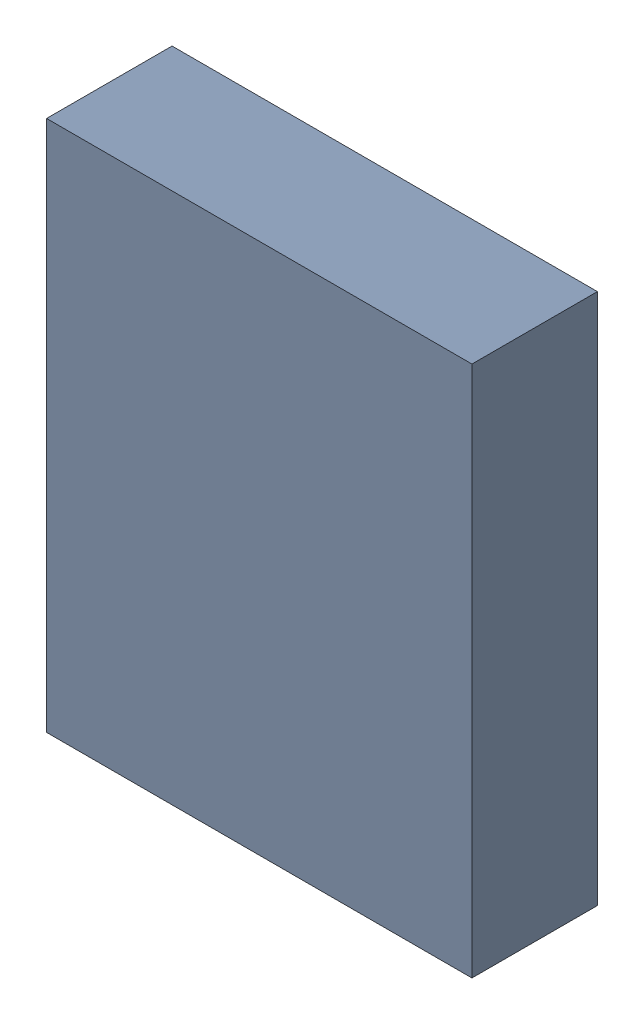
SolidWorks assembly L3, configuration Default. Lengths in mm.
Overall size (1 1.25 0.29).
2 component instances, 1 part files, 0 mates.
Components (placement in the parent):
- 870940800-1: 870940800 [Default] at (41.166 29.531 0.005) size (1 1.25 0.29)
  - Extruded_16-1: Extruded_16 [Default] at origin size (1 1.25 0.29)
